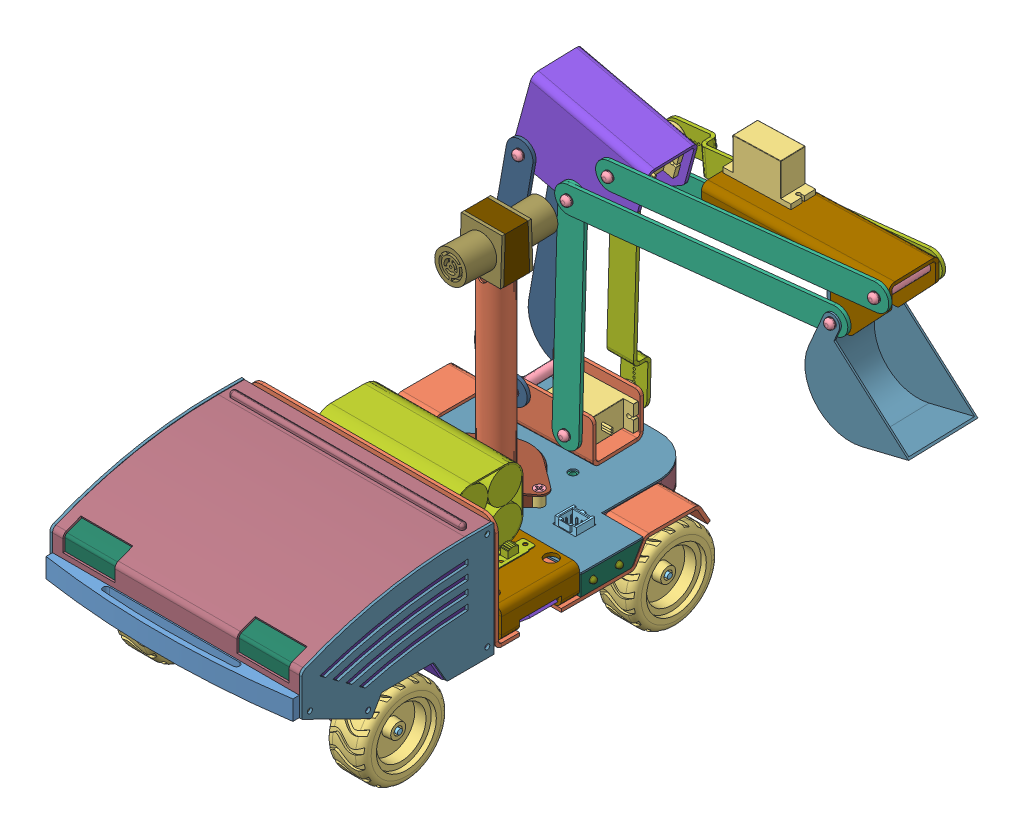
SolidWorks assembly Digger, Test Assembly, configuration Default. Lengths in mm.
Overall size (246.15 210.27 233.07).
117 component instances, 51 part files, 1 mates.
Components (placement in the parent):
- SCOUT, TOP LEVEL-1: SCOUT, TOP LEVEL [Default] at (-160.8858 1.7268 68.3177) size (124.43 158.23 223.86)
  - 6655k13 Thrust Washers-1: 6655k13 Thrust Washers [Default] at (-7.8856 2.7539 2.2902) size (14.15 14.15 4.9)
  - REAR, TOP LEVEL-1: REAR, TOP LEVEL [Default] at (-50.0168 -33.3245 -47.0081) x (-1 0 0) z (0 0 -1) size (124.43 158.23 120.66)
    - PLATE, REAR-1: PLATE, REAR [Default] at (-42.1312 28.0774 12.7174) size (120.65 55.63 120.66)
    - WHEEL ASSEMBLY-1: WHEEL ASSEMBLY [Default-_flexible1] at (7.6153 26.9792 58.7651) x (0 0 1) z (1 0 0) size (42.46 78.6 70.03) (flexible)
      - Pololu 49x19 Wheel-1: Pololu 49x19 Wheel [Default] at (-19.8703 11.8393 2.4418) size (42.46 42.56 19)
      - Pololu Extended Micro Metal Bracket-1: Pololu Extended Micro Metal Bracket [Default] at (-19.8703 6.8393 -18.4366) size (26.6 22.49 26.04)
      - Pololu 298-1 Motor-1: Pololu 298-1 Motor [Default] at (-19.8703 11.8393 -25.1366) x (0 0 -1) z (0 1 0) size (35.87 12 10)
    - WHEEL ASSEMBLY-2: WHEEL ASSEMBLY [Default-_flexible2] at (-91.8778 26.9792 19.0244) x (0 0 -1) z (-1 0 0) size (42.46 78.6 70.03) (flexible)
      - Pololu 49x19 Wheel-1: Pololu 49x19 Wheel [Default] at (-19.8703 11.8393 2.4418) size (42.46 42.56 19)
      - Pololu Extended Micro Metal Bracket-1: Pololu Extended Micro Metal Bracket [Default] at (-19.8703 6.8393 -18.4366) size (26.6 22.49 26.04)
      - Pololu 298-1 Motor-1: Pololu 298-1 Motor [Default] at (-19.8703 11.8393 -25.1366) x (0 0 -1) z (0 1 0) size (35.87 12 10)
    - Socket Head Cap Screw_AI-9: Socket Head Cap Screw_AI [HX-SHCS 0.086-56x0.4375x0.4375-N] at (-77.6912 31.9128 47.8948) x (0 -1 0) z (-0.381305 0 -0.924449) size (13.3 3.56 3.56)
    - Socket Head Cap Screw_AI-10: Socket Head Cap Screw_AI [HX-SHCS 0.086-56x0.4375x0.4375-N] at (-77.6912 31.9128 29.8948) x (0 -1 0) z (0 0 1) size (13.3 3.56 3.56)
    - Socket Head Cap Screw_AI-11: Socket Head Cap Screw_AI [HX-SHCS 0.086-56x0.4375x0.4375-N] at (-6.5712 31.9128 29.8948) x (0 -1 0) z (0 0 1) size (13.3 3.56 3.56)
    - Socket Head Cap Screw_AI-12: Socket Head Cap Screw_AI [HX-SHCS 0.086-56x0.4375x0.4375-N] at (-6.5712 31.9128 47.8948) x (0 -1 0) z (0 0 1) size (13.3 3.56 3.56)
    - 4000mAh 7.4V Battery Pack-1: 4000mAh 7.4V Battery Pack [Default] at (-42.1312 61.2244 -25.7652) x (0 0 -1) z (1 0 0) size (34.29 34.29 68.58)
    - SENSOR, GP2Y0D810-1: SENSOR, GP2Y0D810 [Default] at (9.9271 36.6454 -23.9419) x (0 0 -1) z (0.766044 0.642788 0) size (28.32 10.54 8.89)
    - SENSOR, GP2Y0D810-2: SENSOR, GP2Y0D810 [Default] at (-94.1896 36.6454 -23.9419) x (0 0 -1) z (0.766044 -0.642788 0) size (28.32 10.54 8.89)
    - Battery Support-1: Battery Support [Default] at (-42.1312 29.7284 -26.0192) size (120.65 27.05 38.1)
    - Mounting Block-1: Mounting Block [Default] at (-42.1312 36.0784 -35.6712) x (-1 0 0) z (0 0 -1) size (25.4 12.7 25.4)
    - PF35T-48-1: PF35T-48 [Default] at (-42.1312 31.7284 12.5888) size (50 29.2 35)
    - MaxSonar EZ1-1: MaxSonar EZ1 [Default] at (-42.1312 140.4691 6.6293) x (-1 0 0) z (0 0.034899 -0.999391) size (19.94 22.1 16.38)
    - MaxSonar EZ1-2: MaxSonar EZ1 [Default] at (-42.1312 140.4691 18.5483) x (1 0 0) z (0 0.034899 0.999391) size (19.94 22.1 16.38)
    - BUMPER, REAR-1: BUMPER, REAR [Default] at (-42.1312 29.7284 53.2288) x (-1 0 0) z (0 0 -1) size (80.01 9.53 54.3)
    - PLATE, REAR COVER-1: PLATE, REAR COVER [Default] at (-42.1312 39.2534 72.2788) size (120.65 0.81 81.14)
    - MOUNTING BLOCK, COLOR SENSOR-1: MOUNTING BLOCK, COLOR SENSOR [Default] at (-97.6937 29.7284 5.6038) size (9.53 9.53 30.46)
    - MOUNTING BLOCK, COLOR SENSOR-2: MOUNTING BLOCK, COLOR SENSOR [Default] at (13.4313 29.7284 5.6038) size (9.53 9.53 30.46)
    - SENSOR, COLOR LED-1: SENSOR, COLOR LED [Default] at (-24.0807 23.782 31.9371) x (0 0 -1) z (-0.409692 -0.912224 0) size (5.83 3.66 3.66)
    - SENSOR, COLOR LED-2: SENSOR, COLOR LED [Default] at (-67.3741 22.996 31.9371) x (0 0 -1) z (-0.202984 -0.979182 0) size (5.83 3.66 3.66)
    - COPPER CONTACT-1: COPPER CONTACT [Default] at (-53.2437 34.4909 64.0238) size (15.88 6.35 4.45)
    - COPPER CONTACT-2: COPPER CONTACT [Default] at (-31.0187 34.4909 64.0238) size (15.88 6.35 4.45)
    - MOUNTING BLOCK, SONAR-1: MOUNTING BLOCK, SONAR [Default] at (-42.1312 140.3989 12.5888) x (-1 0 0) z (0 0 -1) size (19.94 22.23 12.7)
    - SHAFT, SONAR MOUNT-1: SHAFT, SONAR MOUNT [Default] at (-42.1312 52.5784 12.5888) x (-0.538443 0 0.842662) z (-0.842662 0 -0.538443) size (4.76 89.41 4.76)
    - SHAFT, SONAR SUPPORT-1: SHAFT, SONAR SUPPORT [Default] at (-42.1312 46.7284 12.5888) x (0.999987 0 0.005105) z (-0.005105 0 0.999987) size (14.22 82.87 14.22)
    - SHAFT, STEPPER SUPPORT-1: SHAFT, STEPPER SUPPORT [Default] at (-63.1312 29.6724 12.5888) size (4.76 16.26 4.76)
    - SHAFT, STEPPER SUPPORT-2: SHAFT, STEPPER SUPPORT [Default] at (-21.1312 29.6724 12.5888) x (0.987866 0 -0.155311) z (0.155311 0 0.987866) size (4.76 16.26 4.76)
    - Flat Head 100 Screw_AI-6: Flat Head 100 Screw_AI [CR-FHM1 0.112-40x0.25x0.25-N] at (-63.1312 46.7284 12.5888) x (0 -1 0) z (0 0 1) size (6.35 4.85 4.85)
    - Flat Head 100 Screw_AI-7: Flat Head 100 Screw_AI [CR-FHM1 0.112-40x0.25x0.25-N] at (-21.1312 46.7284 12.5888) x (0 -1 0) z (0 0 1) size (6.35 4.85 4.85)
    - CONNECTOR, MOLEX 6 PIN-1: CONNECTOR, MOLEX 6 PIN [Default] at (-80.2263 37.7912 12.5433) size (10.34 13.8 9.75)
    - SENSOR, COLOR LED-3: SENSOR, COLOR LED [Default] at (-64.0196 42.7147 3.5765) x (1 0 0) z (0 0.700538 -0.713616) size (5.83 3.66 3.66)
    - SENSOR, COLOR LED-4: SENSOR, COLOR LED [Default] at (-64.0196 42.7147 -9.1235) x (1 0 0) z (0 0.700538 -0.713616) size (5.83 3.66 3.66)
    - SENSOR, COLOR LED-5: SENSOR, COLOR LED [Default] at (-20.2429 42.7147 20.3311) x (-1 0 0) z (0 0.700538 0.713616) size (5.83 3.66 3.66)
    - SENSOR, COLOR LED-6: SENSOR, COLOR LED [Default] at (-20.2429 42.7147 7.6311) x (-1 0 0) z (0 0.700538 0.713616) size (5.83 3.66 3.66)
    - MOUNTING BLOCK, REAR-1: MOUNTING BLOCK, REAR [Default] at (-58.0062 34.4909 31.0038) size (9.53 9.53 28.57)
    - MOUNTING BLOCK, REAR-2: MOUNTING BLOCK, REAR [Default] at (-26.2562 34.4909 31.0038) size (9.53 9.53 28.57)
    - SW3dPS-Sliderswitch-1: SW3dPS-Sliderswitch [Standard] at (-81.1109 44.0794 -21.7288) size (7.4 16 23.2)
  - FRONT, TOP LEVEL-1: FRONT, TOP LEVEL [Default] at (-84.349 -51.7544 28.3431) x (-1 0 0) z (0 0 -1) size (123.38 92.14 123.57)
    - PLATE, FRONT-1: PLATE, FRONT [Default] at (-76.4634 46.5072 -32.0242) size (120.65 12.1 60.8)
    - WHEEL ASSEMBLY-1: WHEEL ASSEMBLY [Default-_flexible3] at (-26.7168 45.4091 2.1802) x (0 0 1) z (1 0 0) size (42.46 78.6 70.03) (flexible)
      - Pololu 49x19 Wheel-1: Pololu 49x19 Wheel [Default] at (-19.8703 11.8393 2.4418) size (42.46 42.56 19)
      - Pololu Extended Micro Metal Bracket-1: Pololu Extended Micro Metal Bracket [Default] at (-19.8703 6.8393 -18.4366) size (26.6 22.49 26.04)
      - Pololu 298-1 Motor-1: Pololu 298-1 Motor [Default] at (-19.8703 11.8393 -25.1366) x (0 0 -1) z (0 1 0) size (35.87 12 10)
    - WHEEL ASSEMBLY-2: WHEEL ASSEMBLY [Default-_flexible4] at (-126.21 45.4091 -37.5605) x (0 0 -1) z (-1 0 0) size (42.46 78.6 70.03) (flexible)
      - Pololu 49x19 Wheel-1: Pololu 49x19 Wheel [Default] at (-19.8703 11.8393 2.4418) size (42.46 42.56 19)
      - Pololu Extended Micro Metal Bracket-1: Pololu Extended Micro Metal Bracket [Default] at (-19.8703 6.8393 -18.4366) size (26.6 22.49 26.04)
      - Pololu 298-1 Motor-1: Pololu 298-1 Motor [Default] at (-19.8703 11.8393 -25.1366) x (0 0 -1) z (0 1 0) size (35.87 12 10)
    - Socket Head Cap Screw_AI-11: Socket Head Cap Screw_AI [HX-SHCS 0.086-56x0.4375x0.4375-N] at (-112.0234 50.3426 -8.6902) x (0 -1 0) z (0.989468 0 0.144748) size (13.3 3.56 3.56)
    - Socket Head Cap Screw_AI-12: Socket Head Cap Screw_AI [HX-SHCS 0.086-56x0.4375x0.4375-N] at (-40.9034 50.3426 -8.6902) x (0 -1 0) z (0.700957 0 0.713204) size (13.3 3.56 3.56)
    - SENSOR, GP2Y0D810-2: SENSOR, GP2Y0D810 [Default] at (-76.7491 52.0249 -21.9932) x (1 0 0) z (0 -0.642788 0.766044) size (28.32 10.54 8.89)
    - BUMPER, FRONT-1: BUMPER, FRONT [Default] at (-76.4634 36.9822 -30.9902) x (-1 0 0) z (0 0 -1) size (69.85 9.53 6.35)
    - Mounting Block-1: Mounting Block [Default] at (-76.4634 54.5082 12.4258) size (25.4 12.7 25.4)
    - Socket Head Shoulder Screw2_AI-2: Socket Head Shoulder Screw2_AI [SHSSCREW 0.25x1.5-N] at (-76.4634 54.5082 2.5706) x (0 0 1) z (-0.728467 -0.685081 0) size (52.4 9.53 9.53)
    - Socket Head Cap Screw_AI-13: Socket Head Cap Screw_AI [HX-SHCS 0.086-56x0.4375x0.4375-N] at (-40.9034 51.2773 -26.6902) x (0 -1 0) z (-0.957829 0 -0.287339) size (13.3 3.56 3.56)
    - Socket Head Cap Screw_AI-14: Socket Head Cap Screw_AI [HX-SHCS 0.086-56x0.4375x0.4375-N] at (-112.0234 51.2773 -26.6902) x (0 -1 0) z (-0.957829 0 -0.287339) size (13.3 3.56 3.56)
    - PCB, MAIN-1: PCB, MAIN [Default] at (-76.4634 67.2082 -21.6044) size (114.3 6.68 88.9)
    - PLATE, FRONT BUMPER-1: PLATE, FRONT BUMPER [Default] at (-76.4634 48.9202 -22.7941) size (120.65 17.91 44.79)
    - COVER, FRONT-1: COVER, FRONT [Default] at (-76.4634 65.9445 25.1258) size (120.65 38.48 93.73)
    - PLATE, FRONT SIDE-1: PLATE, FRONT SIDE [Default] at (-16.1384 46.5072 25.1258) x (0 0 -1) z (1 0 0) size (93.73 55.63 1.27)
    - SW3dPS-USB_mini_B-1: SW3dPS-USB_mini_B [По умолчанию] at (-54.9865 68.8084 -58.5669) x (-1 0 0) z (0 0 -1) (suppressed, hidden)
    - HEADLIGHT COVER, FRONT-1: HEADLIGHT COVER, FRONT [Default] at (-103.1334 74.8345 -67.5842) x (-1 0 0) z (0 0 -1) size (31.75 14.4 11.68)
    - HEADLIGHT COVER, FRONT-2: HEADLIGHT COVER, FRONT [Default] at (-18.0434 74.8345 -67.5842) x (-1 0 0) z (0 0 -1) size (31.75 14.4 11.68)
    - PLATE, FRONT SIDE-2: PLATE, FRONT SIDE [Default] at (-138.0584 46.5072 25.1258) x (0 0 -1) z (1 0 0) size (93.73 55.63 1.27)
    - STRUT, FRONT SIDE-1: STRUT, FRONT SIDE [Default] at (-76.4634 98.9582 21.9508) size (120.65 3.17 6.35)
    - FILTER, FRONT COVER-1: FILTER, FRONT COVER [Default] at (-19.1356 62.8553 14.5951) x (0 0 -1) z (1 0 0) size (76.17 31.33 3)
    - FILTER, FRONT COVER-2: FILTER, FRONT COVER [Default] at (-136.7884 62.8559 13.2551) x (0 0 -1) z (1 0 0) size (76.17 31.33 3)
    - Orb LED-1: Orb LED [Default] at (-118.9744 68.8084 -63.3886) size (6.35 9.53 6.35)
    - Orb LED-2: Orb LED [Default] at (-34.5831 68.8084 -63.3886) size (6.35 9.53 6.35)
  - BUMPER, FRONT SWITCHED-1: BUMPER, FRONT SWITCHED [Default] at (-7.8856 18.9527 98.5308) size (120.65 9.53 7.62)
- Backhoe 2.0-1: Backhoe 2.0 [Default] at (-170.5517 8.4685 -31.361) x (-0.02919 0 -0.999574) z (0.999574 0 -0.02919) size (43.42 164.06 219.8)
  - Servo Assembly - Base-1: Servo Assembly - Base [Default] at origin size (40.16 20.7 41.27)
    - servo mount - base-1: servo mount - base [Default] at origin size (25.4 20.7 41.27)
    - TowerPro SG90 Micro Servo-1: TowerPro SG90 Micro Servo [Default] at (-7.181 9.7282 3.5975) x (0 0 1) z (0 1 0) size (32.41 30.61 12.42)
    - 3-16 shaft with clip ends-4: 3-16 shaft with clip ends [1.13] at (0 16.3022 -15.3778) x (0 -0.585381 -0.810759) z (1 0 0) size (4.76 4.76 33.46)
    - 3-16 shaft with clip ends-5: 3-16 shaft with clip ends [.13] at (-12.7 9.7282 9.1567) x (0 0.629493 -0.777006) z (1 0 0) size (4.76 4.76 8.06)
  - TowerPro SG90 Micro Servo Horn Double-1: TowerPro SG90 Micro Servo Horn Double [Single Horn] at (21.619 9.7282 9.1575) x (0 0.999632 0.027137) z (0 0.027137 -0.999632) size (19.62 4.24 7.16)
  - linkage - straight-1: linkage - straight [4] at (-13.5255 60.5095 10.5361) x (1 0 0) z (0 -0.999632 -0.027137) size (1.65 12.7 114.3)
  - linkage - straight horn-1: linkage - straight horn [4] at (21.619 9.7282 9.1575) x (-1 0 0) z (0 0.027137 -0.999632) size (8.99 114.3 12.7)
  - Servo Assembly - Elbow-1: Servo Assembly - Elbow [Default] at (-41.2479 149.7002 13.8941) x (-1 0 0) z (0 -0.258818 0.965926) size (41.81 39.75 57.15)
    - servo mount - elbow-1: servo mount - elbow [Default] at (-41.1753 2.6245 6.4415) size (25.4 39.75 57.15)
    - TowerPro SG90 Micro Servo-1: TowerPro SG90 Micro Servo [Default] at (-33.9943 15.6159 15.1698) x (0 0 1) z (0 -1 0) size (32.41 30.61 12.42)
    - 3-16 shaft with clip ends-1: 3-16 shaft with clip ends [1.13] at (-41.1753 37.613 -17.371) x (0 0.999623 0.02745) z (-1 0 0) size (4.76 4.76 33.46)
    - 3-16 shaft with clip ends-2: 3-16 shaft with clip ends [1.26] at (-41.1753 37.613 8.029) x (0 -0.741278 0.671198) z (-1 0 0) size (4.76 4.76 36.77)
    - 3-16 shaft with clip ends-3: 3-16 shaft with clip ends [.13] at (-28.4753 15.6159 20.729) x (0 0.107835 0.994169) z (-1 0 0) size (4.76 4.76 8.06)
  - linkage - straight-4: linkage - straight [5] at (-13.5981 134.3632 93.1698) x (1 0 0) z (0 0.080506 0.996754) size (1.65 12.7 139.7)
  - linkage - straight horn-2: linkage - straight horn [5] at (21.5464 129.2511 29.8759) x (-1 0 0) z (0 0.996754 -0.080506) size (8.99 139.7 12.7)
  - TowerPro SG90 Micro Servo Horn Double-2: TowerPro SG90 Micro Servo Horn Double [Single Horn] at (21.5464 129.2511 29.8759) x (0 0.080506 0.996754) z (0 0.996754 -0.080506) size (19.62 4.24 7.16)
  - linkage - straight-5: linkage - straight [5] at (15.1039 116.4032 75.2085) x (1 0 0) z (0 0.080511 0.996754) size (1.65 12.7 139.7)
  - linkage - straight-6: linkage - straight [5] at (-15.1765 116.4032 75.2085) x (-1 0 0) z (0 0.080511 0.996754) size (1.65 12.7 139.7)
  - Servo Assembly - Wrist-1: Servo Assembly - Wrist [Default] at (-1.9728 133.2455 116.0206) x (1 0 0) z (0 -0.000045 1) size (39.69 48.46 88.9)
    - servo mount - wrist-1: servo mount - wrist [Default] at (1.8276 10.9308 0.7553) size (25.4 30.23 88.9)
    - 3-16 shaft with clip ends-1: 3-16 shaft with clip ends [1.375] at (1.8276 -11.7288 22.4823) x (0 0.988665 0.150141) z (-1 0 0) size (4.76 4.76 39.69)
    - 3-16 shaft with clip ends-2: 3-16 shaft with clip ends [1.13] at (1.8276 6.2318 40.4428) x (0 0.965302 -0.261136) z (-1 0 0) size (4.76 4.76 33.46)
    - TowerPro SG90 Micro Servo-1: TowerPro SG90 Micro Servo [Default] at (5.1663 30.8118 -26.6547) x (0 0 -1) z (-1 0 0) size (32.41 30.61 12.42)
  - linkage - curved-1: linkage - curved [Default] at (13.5255 67.0835 -13.9989) x (1 0 0) z (0 0.999632 0.027145) size (1.65 25.4 114.3)
  - linkage - curved-2: linkage - curved [Default] at (-13.5255 67.0835 -13.9989) x (1 0 0) z (0 0.999632 0.027145) size (1.65 25.4 114.3)
  - TowerPro SG90 Micro Servo Horn Double-3: TowerPro SG90 Micro Servo Horn Double [cutoff] at (3.1935 136.4987 83.806) x (1 0 0.000835) z (-0.000835 -0.000045 1) size (13.11 4.24 7.16)
  - Horn Clip-1: Horn Clip [Default] at (3.1935 135.6732 83.806) x (-0.000835 -0.000045 1) z (-1 0 -0.000835) size (11.93 1.65 22)
  - 3-16 shaft with clip ends-1: 3-16 shaft with clip ends [.173] at (15.2585 134.3016 83.816) x (-0.691689 -0.000032 0.722195) z (0 1 0.000045) size (4.76 4.76 9.16)
  - linkage - thin-1: linkage - thin [Default] at (15.2585 132.93 83.8159) x (0 -1 -0.000045) z (-0.606445 -0.000036 0.795126) size (1.65 7.94 33.34)
  - bucket clevis-1: bucket clevis [Default] at (-0.1452 132.9287 112.7434) x (1 0 0) z (0 0.000045 -1) size (7.94 7.94 16.67)
  - 3-16 shaft with clip ends-2: 3-16 shaft with clip ends [.443] at (-0.1452 132.9287 112.7434) x (0 -0.257698 0.966225) z (-1 0 0) size (4.76 4.76 16.01)
  - 3-16 shaft with clip ends-3: 3-16 shaft with clip ends [.313] at (-0.1452 132.9354 104.0121) x (0.995998 0.000004 -0.089372) z (0 1 0.000045) size (4.76 4.76 12.71)
  - bucket-1: bucket [Default] at (-0.1452 97.7557 148.174) x (1 0 0) z (0 -0.684818 0.728714) size (34.93 43.12 69.19)
  - 3-16 shaft with clip ends-4: 3-16 shaft with clip ends [.625] at (-0.1452 133.3987 134.9634) x (0 0.049316 0.998783) z (-1 0 0) size (4.76 4.76 20.64)
  - linkage - thin-2: linkage - thin [.875] at (4.6554 132.9287 112.7434) x (1 0 0) z (0 0.021148 0.999776) size (1.65 7.94 30.16)
  - linkage - thin-3: linkage - thin [.875] at (-4.9458 132.9287 112.7434) x (1 0 0) z (0 0.021148 0.999776) size (1.65 7.94 30.16)
Mates (geometry in assembly coordinates):
- Coincident1: coincident anti-aligned: plane of SCOUT, TOP LEVEL-1/REAR, TOP LEVEL-1/PLATE, REAR COVER-1 through (-149.0474 8.4685 -30.6604) normal (0 1 0); plane of Backhoe 2.0-1/Servo Assembly - Base-1/servo mount - base-1 through (-149.5523 8.4685 -19.2688) normal (0 -1 0)
